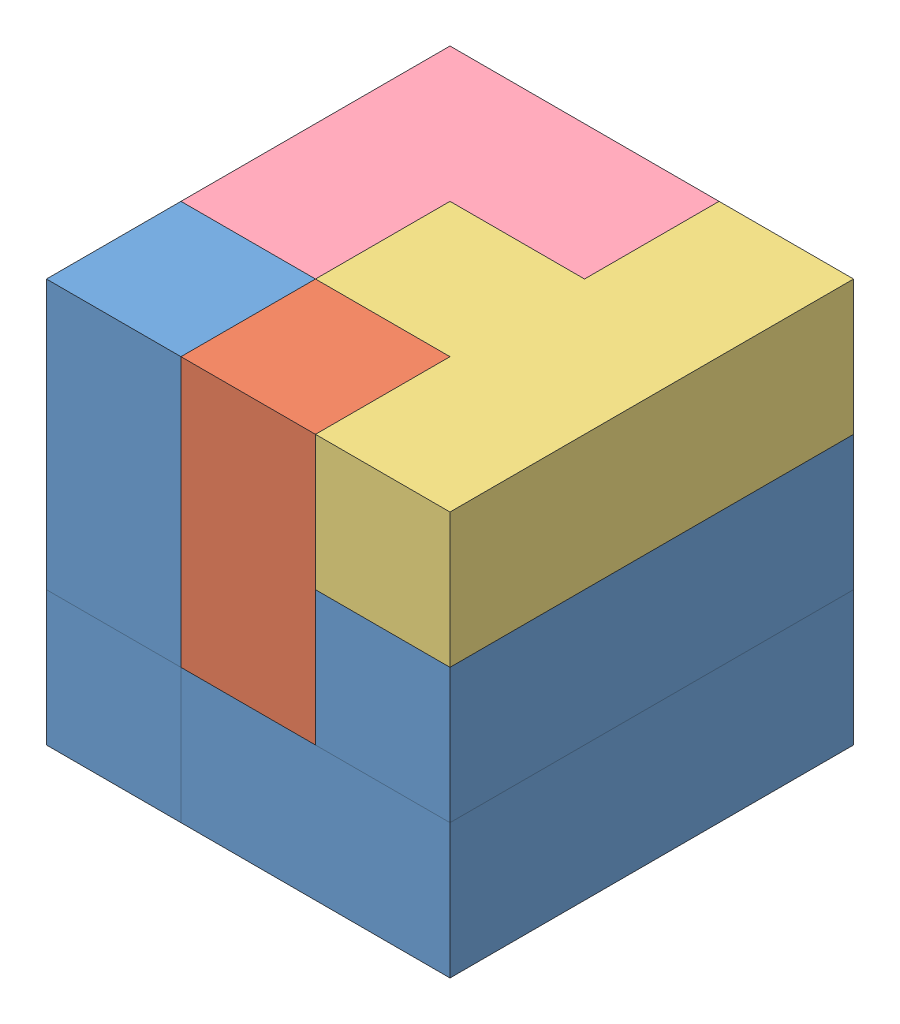
SolidWorks assembly Assemfinal, configuration Default. Lengths in mm.
Overall size (90 90 90).
10 component instances, 4 part files, 2 mates.
Components (placement in the parent):
- Assem3-1: Assem3 [Default] at (26.0429 -5.6264 9.5826) size (90 30 90)
  - task2Part1-1: task2Part1 [Default] at (54.3963 11.6731 83.9325) x (0 0 -1) z (0 1 0) size (90 60 30)
  - task2Part1-2: task2Part1 [Default] at (-35.6037 11.6731 -6.0675) x (0 0 1) z (0 1 0) size (90 60 30)
- Assem2-1: Assem2 [Default] at (37.5035 -31.8061 48.7347) x (0 1 0) z (1 0 0) size (90 90 90)
  - task2part4-2: task2part4 [Default] at (37.8527 -15.2196 -17.0642) size (90 60 30)
  - task2Part1-2: task2Part1 [Default] at (97.8527 -45.2196 42.9358) x (0 1 0) z (-1 0 0) size (90 60 30)
  - task2Part1-5: task2Part1 [Default] at (67.8527 44.7804 -47.0642) x (0 -1 0) z (0 0 1) size (90 60 30)
- Assem1-2: Assem1 [Default] at (112.2312 -7.1299 78.5468) x (0 0 -1) z (0 1 0) size (90 90 30)
  - task2Part2-1: task2Part2 [Default] at (-14.9683 31.792 73.1766) size (90 60 30)
  - task2Part3-1: task2Part3 [Default] at (75.0317 61.792 73.1766) x (0 1 0) z (0 0 1) size (60 60 30)
Mates (geometry in assembly coordinates):
- Coincident1: coincident: point of Assem3-1/task2Part1-1; point of Assem2-1/task2part4-2
- Coincident3: coincident: point of Assem2-1/task2part4-2; point of Assem1-2/task2Part2-1
